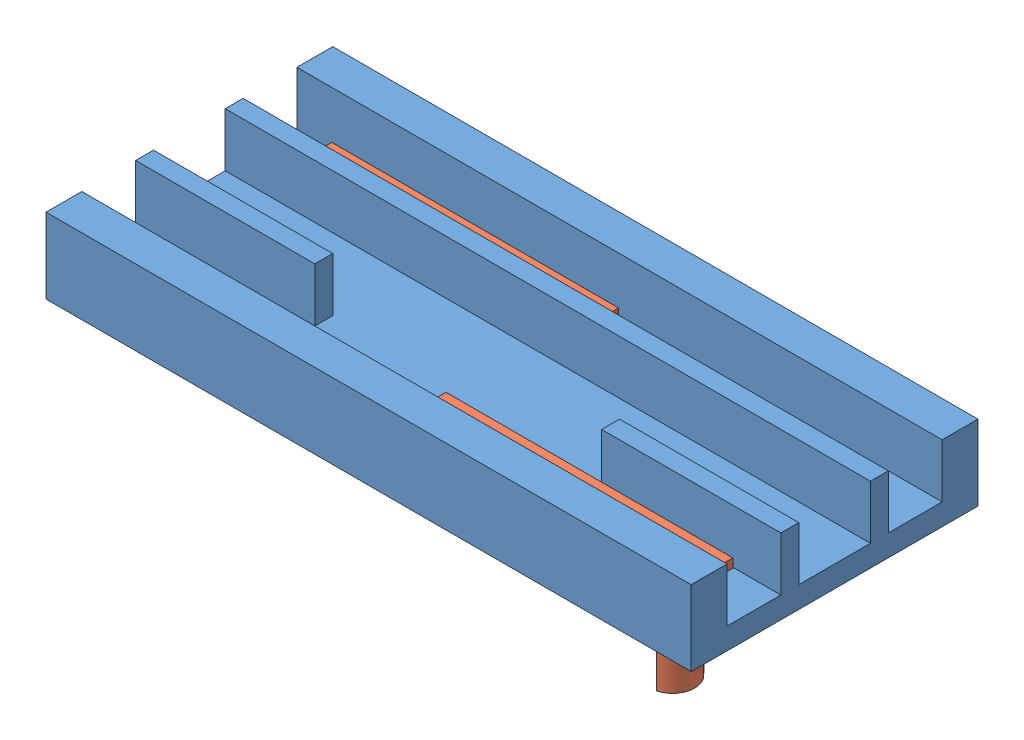
SolidWorks assembly Assem3, configuration Default. Lengths in mm.
Overall size (228.6 53.97 101.6).
3 component instances, 2 part files, 4 mates.
Components (placement in the parent):
- base-1: base [Default] at (-26.3084 96.3441 231.3993) size (228.6 26.67 101.6)
- gripper-1: gripper [Default] at (-12.97 103.9641 161.2642) size (101.6 38.1 17.78)
- gripper-2: gripper [Default] at (185.57 103.9641 199.9344) x (-1 0 0) z (0 0 -1) size (101.6 38.1 17.78)
Mates (geometry in assembly coordinates):
- Coincident1: coincident anti-aligned: plane of base-1 through (-0.9084 96.3441 147.8907) normal (0 0 1); plane of gripper-1 through (82.28 97.6141 147.8907) normal (0 0 -1)
- Coincident2: coincident anti-aligned: plane of base-1 through (-26.3084 103.9641 231.3993) normal (0 1 0); plane of gripper-1 through (-12.97 103.9641 161.2642) normal (0 -1 0)
- Coincident3: coincident anti-aligned: plane of base-1 through (-0.9084 96.3441 213.3079) normal (0 0 -1); plane of gripper-2 through (90.32 97.6141 213.3079) normal (0 0 1)
- Coincident4: coincident anti-aligned: plane of base-1 through (-26.3084 103.9641 231.3993) normal (0 1 0); plane of gripper-2 through (185.57 103.9641 199.9344) normal (0 -1 0)
